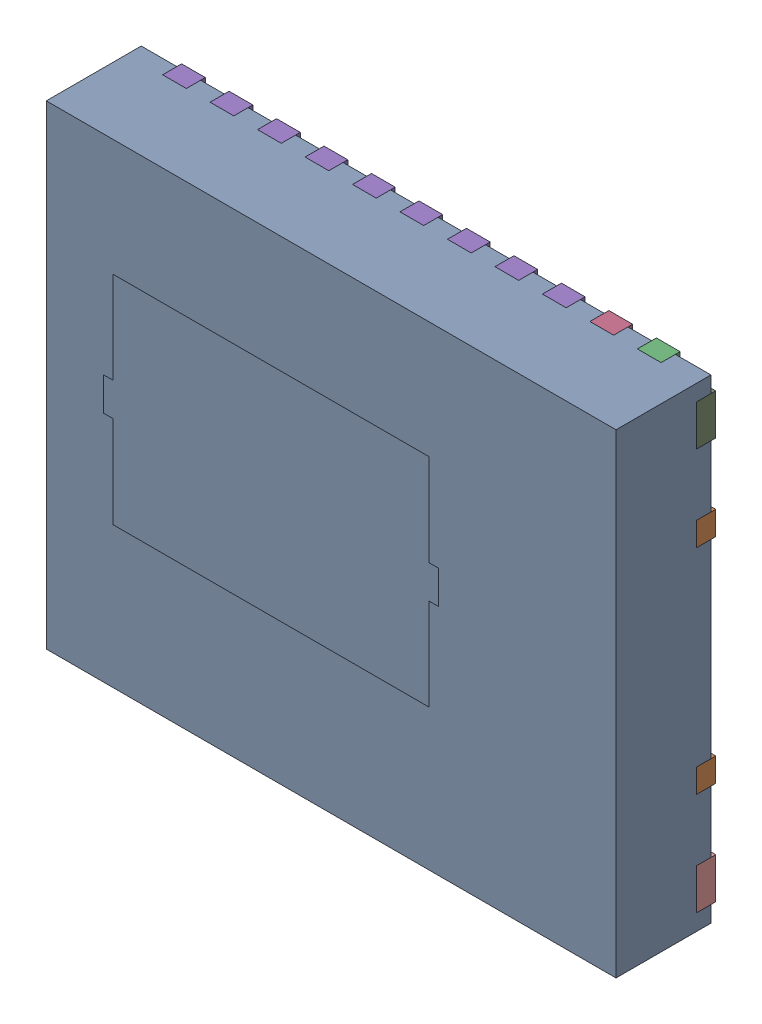
SolidWorks assembly U2, configuration Default. Lengths in mm.
Overall size (6 5 1.05).
15 component instances, 13 part files, 0 mates.
Components (placement in the parent):
- DMM0022A-1: DMM0022A [Default] at (40.1321 42.5449 0) x (0 -1 0) z (0 0 1) size (5 6 1.05)
  - BODY-SON-1: BODY-SON [Default] at (0 0 0.05) x (1 0 0) z (0 -1 0) size (5 1 6)
  - FRAME-DMM0022A-1: FRAME-DMM0022A [Default] x (1 0 0) z (0 -1 0) size (5 0.2 6)
    - Open CASCADE STEP translator 7.5 1.2.1.2.1-1: Open CASCADE STEP translator 7.5 1.2.1.2.1 [Default] at origin size (3.5 0.2 6)
    - Open CASCADE STEP translator 7.5 1.2.1.2.2-1: Open CASCADE STEP translator 7.5 1.2.1.2.2 [Default] at origin size (0.5 0.2 0.25)
    - Open CASCADE STEP translator 7.5 1.2.1.2.3-1: Open CASCADE STEP translator 7.5 1.2.1.2.3 [Default] at origin size (0.5 0.2 0.25)
    - Open CASCADE STEP translator 7.5 1.2.1.2.4-1: Open CASCADE STEP translator 7.5 1.2.1.2.4 [Default] at origin size (0.5 0.2 4.25)
    - Open CASCADE STEP translator 7.5 1.2.1.2.5-1: Open CASCADE STEP translator 7.5 1.2.1.2.5 [Default] at origin size (0.5 0.2 0.25)
    - Open CASCADE STEP translator 7.5 1.2.1.2.6-1: Open CASCADE STEP translator 7.5 1.2.1.2.6 [Default] at origin size (0.5 0.2 0.25)
    - Open CASCADE STEP translator 7.5 1.2.1.2.7-1: Open CASCADE STEP translator 7.5 1.2.1.2.7 [Default] at origin size (0.5 0.2 4.25)
    - Open CASCADE STEP translator 7.5 1.2.1.2.8-1: Open CASCADE STEP translator 7.5 1.2.1.2.8 [Default] at origin size (0.43 0.2 0.18)
    - Open CASCADE STEP translator 7.5 1.2.1.2.9-1: Open CASCADE STEP translator 7.5 1.2.1.2.9 [Default] at origin size (0.43 0.2 0.18)
    - Open CASCADE STEP translator 7.5 1.2.1.2.10-1: Open CASCADE STEP translator 7.5 1.2.1.2.10 [Default] at origin size (0.43 0.2 0.18)
    - Open CASCADE STEP translator 7.5 1.2.1.2.11-1: Open CASCADE STEP translator 7.5 1.2.1.2.11 [Default] at origin size (0.43 0.2 0.18)
  - HEATSLUG-1: HEATSLUG [Default] at (-0.128 -0.635 0.958) x (1 0 0) z (0 -1 0) size (2.28 0.09 3.53)
